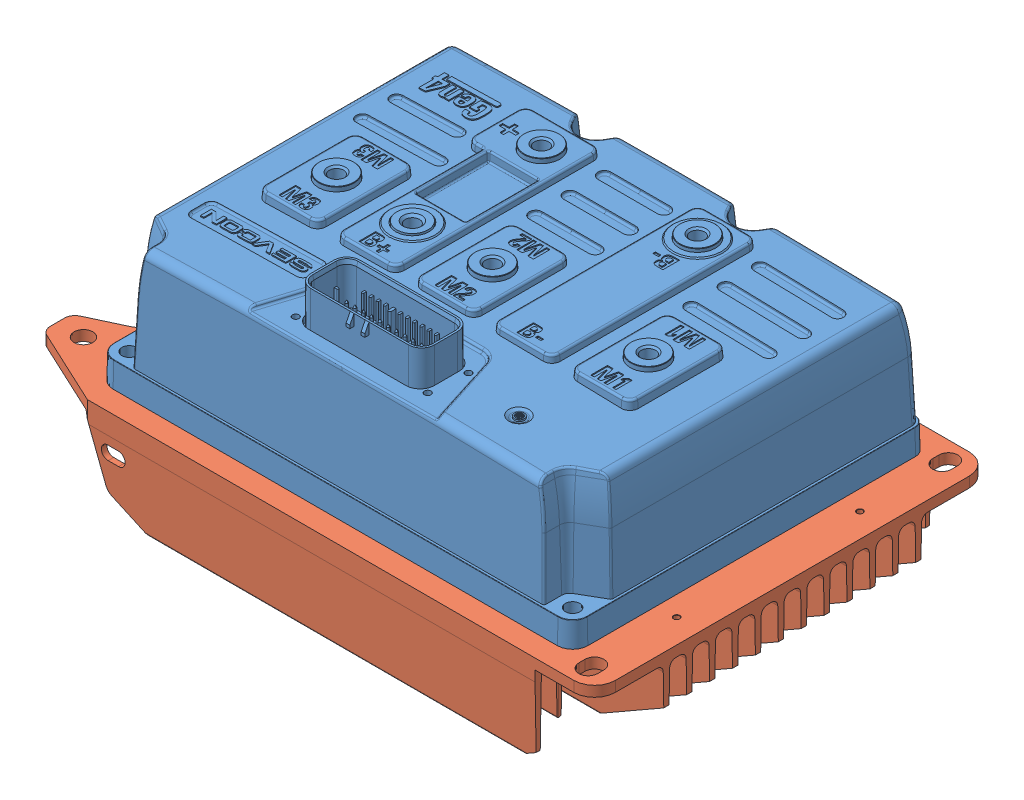
SolidWorks assembly GEN 4 SIZE 4, MOTOR CONTROLLER + HEATSINK, SEVCON, configuration Default. Lengths in mm.
Overall size (283 120.54 190).
2 component instances, 2 part files, 3 mates.
Components (placement in the parent):
- GEN 4 SIZE 4, MOTOR CONTROLLER, SEVCON-1: GEN 4 SIZE 4, MOTOR CONTROLLER, SEVCON [Default] at (52.75 88.4563 186.4833) size (228.03 77.65 170.03)
- GEN 4 SIZE 4, HEAT SINK, SEVCON-1: GEN 4 SIZE 4, HEAT SINK, SEVCON [Default] at (46.3 89.8063 181.4833) x (0 0 -1) z (1 0 0) size (190 42.89 283)
Mates (geometry in assembly coordinates):
- Concentric5: concentric: cone of GEN 4 SIZE 4, MOTOR CONTROLLER, SEVCON-1 through (15.3 88.4563 108.4833) axis (0 1 0); cylinder of GEN 4 SIZE 4, HEAT SINK, SEVCON-1 through (15.3 80.5086 108.4833) axis (0 1 0) radius 3.5
- Coincident1: coincident: plane of GEN 4 SIZE 4, MOTOR CONTROLLER, SEVCON-1 through (161.45 88.4563 106.7833) normal (0 -1 0); plane of GEN 4 SIZE 4, HEAT SINK, SEVCON-1 through (504.3645 88.4563 99.4826) normal (0 1 0)
- Parallel5: parallel anti-aligned: plane of GEN 4 SIZE 4, MOTOR CONTROLLER, SEVCON-1 through (52.75 88.4563 186.4833) normal (0 0 1); plane of GEN 4 SIZE 4, HEAT SINK, SEVCON-1 through (46.3 89.8063 181.4833) normal (0 0 -1)
